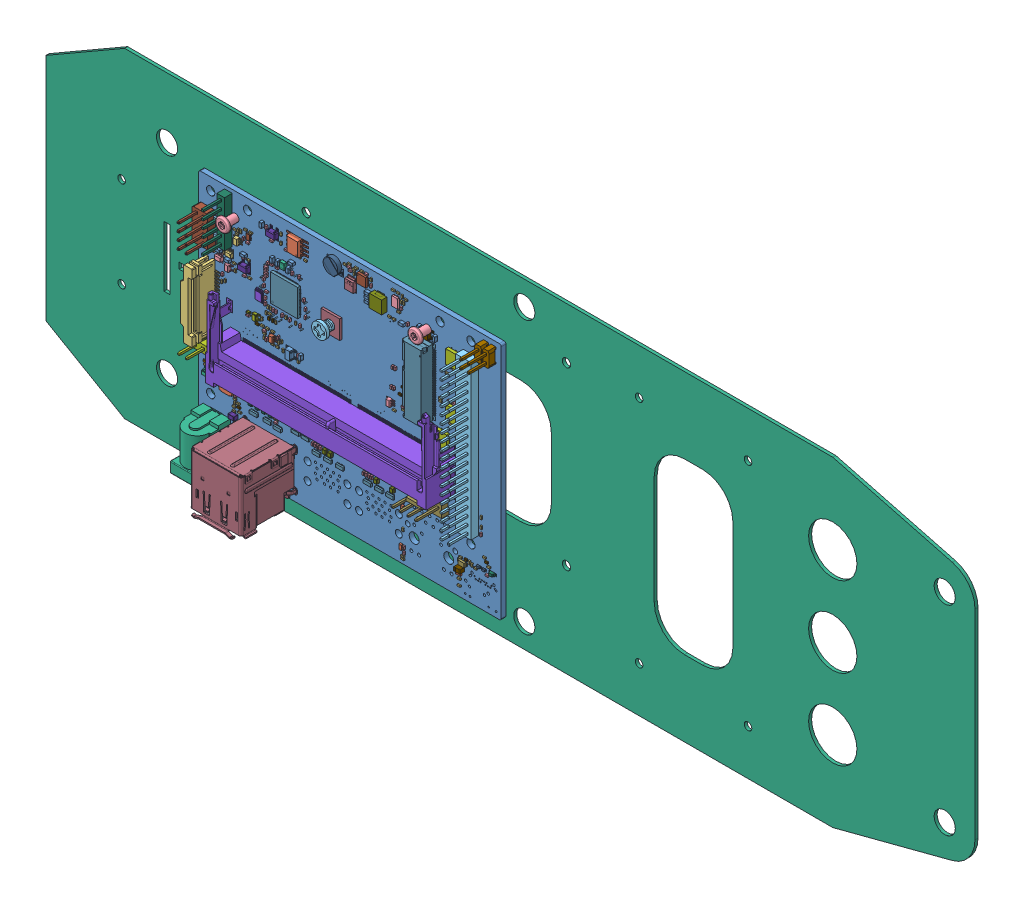
SolidWorks assembly Assemblage, configuration Défaut. Lengths in mm.
Overall size (307 106 29.95).
397 component instances, 67 part files, 3 mates.
Components (placement in the parent):
- P3450_P3449_A02_P3448_A02-1: P3450_P3449_A02_P3448_A02 [Défaut] at (-61.123 -7.2798 -13.0275) size (100 81.03 30.21)
  - 142-13449-1000-A02_ASM-1: 142-13449-1000-A02_ASM [Défaut] at origin size (100 81.03 22.88)
    - 142-13449-1000-A02-1: 142-13449-1000-A02 [Défaut] at origin size (100 79 1.57)
    - 315-1109-000_1-1: 315-1109-000_1 [Défaut] at (5.6 4.9 1.575) x (-1 0 0) z (0 0 1) size (4.5 3.5 0.8)
    - 0402_H040-1: 0402_H040 [Défaut] at (8 -0.825 1.575) size (1 0.5 0.4)
    - 0402_H060-1: 0402_H060 [Défaut] at (1 5 1.575) x (0 -1 0) z (0 0 1) size (1 0.5 0.6)
    - 0402_H040-2: 0402_H040 [Défaut] at (9.9 -0.3 1.575) size (1 0.5 0.4)
    - 0402_H040-3: 0402_H040 [Défaut] at (8.296 51.194 1.575) x (-1 0 0) z (0 0 1) size (1 0.5 0.4)
    - 0402_H040-4: 0402_H040 [Défaut] at (76.2 36.9 1.575) x (-1 0 0) z (0 0 1) size (1 0.5 0.4)
    - 0402_H040-5: 0402_H040 [Défaut] at (37.8 2.87 1.575) x (0 -1 0) z (0 0 1) size (1 0.5 0.4)
    - 0402_H040-6: 0402_H040 [Défaut] at (38.6 2.87 1.575) x (0 -1 0) z (0 0 1) size (1 0.5 0.4)
    - 0402_H060-2: 0402_H060 [Défaut] at (14.2 7.7 1.575) x (0 -1 0) z (0 0 1) size (1 0.5 0.6)
    - 0402_H040-7: 0402_H040 [Défaut] at (64 27.5 1.575) x (-1 0 0) z (0 0 1) size (1 0.5 0.4)
    - 0402_H060-3: 0402_H060 [Défaut] at (18.6 43.15 1.575) x (-1 0 0) z (0 0 1) size (1 0.5 0.6)
    - 0402_H060-4: 0402_H060 [Défaut] at (65.5 52.8 1.575) x (0 1 0) z (0 0 1) size (1 0.5 0.6)
    - 0402_H060-5: 0402_H060 [Défaut] at (64 28.4 1.575) x (-1 0 0) z (0 0 1) size (1 0.5 0.6)
    - 0402_H040-8: 0402_H040 [Défaut] at (60.95 25.85 1.575) size (1 0.5 0.4)
    - 0402_H060-6: 0402_H060 [Défaut] at (17.3 7.7 1.575) x (0 -1 0) z (0 0 1) size (1 0.5 0.6)
    - 0402_H060-7: 0402_H060 [Défaut] at (18.6 7.7 1.575) x (0 -1 0) z (0 0 1) size (1 0.5 0.6)
    - 0402_H060-8: 0402_H060 [Défaut] at (12.9 7.7 1.575) x (0 -1 0) z (0 0 1) size (1 0.5 0.6)
    - 0402_H060-9: 0402_H060 [Défaut] at (80.9 37.7 1.575) x (-1 0 0) z (0 0 1) size (1 0.5 0.6)
    - 0402_H040-9: 0402_H040 [Défaut] at (79.5 31.3 1.575) size (1 0.5 0.4)
    - 0402_H040-10: 0402_H040 [Défaut] at (81 31.3 1.575) x (-1 0 0) z (0 0 1) size (1 0.5 0.4)
    - 0402_H060-10: 0402_H060 [Défaut] at (79.3 37.7 1.575) size (1 0.5 0.6)
    - 0402_H060-11: 0402_H060 [Défaut] at (74.8 4.05 1.575) x (-1 0 0) z (0 0 1) size (1 0.5 0.6)
    - 0402_H040-11: 0402_H040 [Défaut] at (65.675 6.15 1.575) x (0 -1 0) z (0 0 1) size (1 0.5 0.4)
    - 0402_H060-12: 0402_H060 [Défaut] at (67.7 6.85 1.575) x (0 1 0) z (0 0 1) size (1 0.5 0.6)
    - 0402_H040-12: 0402_H040 [Défaut] at (64.475 5.8 1.575) x (-1 0 0) z (0 0 1) size (1 0.5 0.4)
    - 0402_H040-13: 0402_H040 [Défaut] at (67.725 5.325 1.575) x (0 1 0) z (0 0 1) size (1 0.5 0.4)
    - 0402_H060-13: 0402_H060 [Défaut] at (46.1 59.45 1.575) size (1 0.5 0.6)
    - 0402_H040-14: 0402_H040 [Défaut] at (44.65 59.45 1.575) size (1 0.5 0.4)
    - 0402_H040-15: 0402_H040 [Défaut] at (46.1 60.25 1.575) size (1 0.5 0.4)
    - 0402_H060-14: 0402_H060 [Défaut] at (53.35 57.7 1.575) x (0 -1 0) z (0 0 1) size (1 0.5 0.6)
    - 0402_H040-16: 0402_H040 [Défaut] at (47.6 59.45 1.575) size (1 0.5 0.4)
    - 0402_H040-17: 0402_H040 [Défaut] at (48.4 60.25 1.575) size (1 0.5 0.4)
    - 0402_H040-18: 0402_H040 [Défaut] at (47.7 58.325 1.575) x (0 1 0) z (0 0 1) size (1 0.5 0.4)
    - 0402_H060-15: 0402_H060 [Défaut] at (46.5 58.65 1.575) x (-1 0 0) z (0 0 1) size (1 0.5 0.6)
    - 0402_H060-16: 0402_H060 [Défaut] at (51.8 60.25 1.575) size (1 0.5 0.6)
    - 0402_H040-19: 0402_H040 [Défaut] at (53.35 59.4 1.575) x (0 -1 0) z (0 0 1) size (1 0.5 0.4)
    - 0402_H040-20: 0402_H040 [Défaut] at (50.2 60.25 1.575) x (-1 0 0) z (0 0 1) size (1 0.5 0.4)
    - 0402_H060-17: 0402_H060 [Défaut] at (18.6 43.95 1.575) x (-1 0 0) z (0 0 1) size (1 0.5 0.6)
    - 0402_H060-18: 0402_H060 [Défaut] at (52.75 2.9 1.575) x (0 -1 0) z (0 0 1) size (1 0.5 0.6)
    - 0402_H060-19: 0402_H060 [Défaut] at (22.35 47.4 1.575) x (-1 0 0) z (0 0 1) size (1 0.5 0.6)
    - 0402_H060-20: 0402_H060 [Défaut] at (20.55 47.4 1.575) x (-1 0 0) z (0 0 1) size (1 0.5 0.6)
    - 0402_H060-21: 0402_H060 [Défaut] at (21.95 34.55 1.575) x (0 -1 0) z (0 0 1) size (1 0.5 0.6)
    - 0402_H060-22: 0402_H060 [Défaut] at (21.05 34.55 1.575) x (0 -1 0) z (0 0 1) size (1 0.5 0.6)
    - 0402_H060-23: 0402_H060 [Défaut] at (53.55 2.9 1.575) x (0 -1 0) z (0 0 1) size (1 0.5 0.6)
    - 0402_H060-24: 0402_H060 [Défaut] at (25.4 54 1.575) x (-1 0 0) z (0 0 1) size (1 0.5 0.6)
    - 0402_H060-25: 0402_H060 [Défaut] at (24 34.58 1.575) x (0 -1 0) z (0 0 1) size (1 0.5 0.6)
    - 0402_H040-21: 0402_H040 [Défaut] at (55.6 2.95 1.575) x (0 -1 0) z (0 0 1) size (1 0.5 0.4)
    - 0402_H040-22: 0402_H040 [Défaut] at (20.13 34.53 1.575) x (0 1 0) z (0 0 1) size (1 0.5 0.4)
    - 0402_H060-26: 0402_H060 [Défaut] at (18.4 35.15 1.575) x (0 1 0) z (0 0 1) size (1 0.5 0.6)
    - 0402_H060-27: 0402_H060 [Défaut] at (18.4 36.75 1.575) x (0 1 0) z (0 0 1) size (1 0.5 0.6)
    - 0402_H040-23: 0402_H040 [Défaut] at (39.6 2.87 1.575) x (0 -1 0) z (0 0 1) size (1 0.5 0.4)
    - 0402_H040-24: 0402_H040 [Défaut] at (40.4 2.87 1.575) x (0 -1 0) z (0 0 1) size (1 0.5 0.4)
    - 0402_H040-25: 0402_H040 [Défaut] at (60.95 2.95 1.575) x (0 -1 0) z (0 0 1) size (1 0.5 0.4)
    - 0402_H040-26: 0402_H040 [Défaut] at (60.15 2.95 1.575) x (0 -1 0) z (0 0 1) size (1 0.5 0.4)
    - 0402_H040-27: 0402_H040 [Défaut] at (54.8 2.95 1.575) x (0 -1 0) z (0 0 1) size (1 0.5 0.4)
    - 0402_H040-28: 0402_H040 [Défaut] at (31.6 54 1.575) size (1 0.5 0.4)
    - 0402_H040-29: 0402_H040 [Défaut] at (27.4 54 1.575) size (1 0.5 0.4)
    - 0402_H040-30: 0402_H040 [Défaut] at (29.6 54 1.575) x (-1 0 0) z (0 0 1) size (1 0.5 0.4)
    - 0402_H040-31: 0402_H040 [Défaut] at (63.775 -14.475 1.575) size (1 0.5 0.4)
    - 0402_H040-32: 0402_H040 [Défaut] at (63.775 -15.275 1.575) size (1 0.5 0.4)
    - 0402_H040-33: 0402_H040 [Défaut] at (8.025 41.475 1.575) x (-1 0 0) z (0 0 1) size (1 0.5 0.4)
    - 0402_H060-28: 0402_H060 [Défaut] at (63.95 1.25 1.575) x (0 1 0) z (0 0 1) size (1 0.5 0.6)
    - 0402_H060-29: 0402_H060 [Défaut] at (2.95 54.05 1.575) x (0 1 0) z (0 0 1) size (1 0.5 0.6)
    - 0402_H040-34: 0402_H040 [Défaut] at (92.2 -3.45 1.575) x (-1 0 0) z (0 0 1) size (1 0.5 0.4)
    - 0402_H060-30: 0402_H060 [Défaut] at (32.85 7.7 1.575) x (0 -1 0) z (0 0 1) size (1 0.5 0.6)
    - 0402_H060-31: 0402_H060 [Défaut] at (27.25 7.7 1.575) x (0 -1 0) z (0 0 1) size (1 0.5 0.6)
    - 0402_H060-32: 0402_H060 [Défaut] at (31.25 7.7 1.575) x (0 -1 0) z (0 0 1) size (1 0.5 0.6)
    - 0402_H060-33: 0402_H060 [Défaut] at (28.85 7.7 1.575) x (0 -1 0) z (0 0 1) size (1 0.5 0.6)
    - 0402_H060-34: 0402_H060 [Défaut] at (32.05 7.7 1.575) x (0 -1 0) z (0 0 1) size (1 0.5 0.6)
    - 0402_H060-35: 0402_H060 [Défaut] at (28.05 7.7 1.575) x (0 -1 0) z (0 0 1) size (1 0.5 0.6)
    - 0402_H060-36: 0402_H060 [Défaut] at (30.45 7.7 1.575) x (0 -1 0) z (0 0 1) size (1 0.5 0.6)
    - 0402_H060-37: 0402_H060 [Défaut] at (29.65 7.7 1.575) x (0 -1 0) z (0 0 1) size (1 0.5 0.6)
    - 0402_H060-38: 0402_H060 [Défaut] at (24.65 6.41 1.575) x (0 -1 0) z (0 0 1) size (1 0.5 0.6)
    - 0402_H060-39: 0402_H060 [Défaut] at (25.85 6.41 1.575) x (0 -1 0) z (0 0 1) size (1 0.5 0.6)
    - 0402_H060-40: 0402_H060 [Défaut] at (4.2 36.5 1.575) x (0 1 0) z (0 0 1) size (1 0.5 0.6)
    - 0402_H060-41: 0402_H060 [Défaut] at (89.7 4.7 1.575) x (0 -1 0) z (0 0 1) size (1 0.5 0.6)
    - 0402_H060-42: 0402_H060 [Défaut] at (82.5 3.8 1.575) x (0 -1 0) z (0 0 1) size (1 0.5 0.6)
    - 0402_H060-43: 0402_H060 [Défaut] at (12.65 49.7 1.575) size (1 0.5 0.6)
    - 0402_H060-44: 0402_H060 [Défaut] at (11.2 50.15 1.575) x (0 -1 0) z (0 0 1) size (1 0.5 0.6)
    - 0402_H060-45: 0402_H060 [Défaut] at (26.5 34.55 1.575) x (0 -1 0) z (0 0 1) size (1 0.5 0.6)
    - 0402_H060-46: 0402_H060 [Défaut] at (29.9 34.5 1.575) x (0 -1 0) z (0 0 1) size (1 0.5 0.6)
    - 0402_H060-47: 0402_H060 [Défaut] at (31.7 40.15 1.575) x (0 1 0) z (0 0 1) size (1 0.5 0.6)
    - 0402_H060-48: 0402_H060 [Défaut] at (31.15 42.5 1.575) x (0 1 0) z (0 0 1) size (1 0.5 0.6)
    - 0402_H060-49: 0402_H060 [Défaut] at (19.2 47.05 1.575) x (0 1 0) z (0 0 1) size (1 0.5 0.6)
    - 0402_H060-50: 0402_H060 [Défaut] at (17.95 42 1.575) x (0 -1 0) z (0 0 1) size (1 0.5 0.6)
    - 0402_H060-51: 0402_H060 [Défaut] at (27.3 48.25 1.575) x (0 1 0) z (0 0 1) size (1 0.5 0.6)
    - 0402_H060-52: 0402_H060 [Défaut] at (31.7 37.85 1.575) x (0 -1 0) z (0 0 1) size (1 0.5 0.6)
    - 0402_H060-53: 0402_H060 [Défaut] at (29.6 48.35 1.575) x (0 1 0) z (0 0 1) size (1 0.5 0.6)
    - 0402_H060-54: 0402_H060 [Défaut] at (18.8 38.75 1.575) x (-1 0 0) z (0 0 1) size (1 0.5 0.6)
    - 0402_H060-55: 0402_H060 [Défaut] at (18.7 57.2 1.575) x (0 -1 0) z (0 0 1) size (1 0.5 0.6)
    - 0402_H060-56: 0402_H060 [Défaut] at (34.1 2.9 1.575) x (0 -1 0) z (0 0 1) size (1 0.5 0.6)
    - 0402_H060-57: 0402_H060 [Défaut] at (35.8 2.9 1.575) x (0 -1 0) z (0 0 1) size (1 0.5 0.6)
    - 0402_H060-58: 0402_H060 [Défaut] at (34.9 2.9 1.575) x (0 -1 0) z (0 0 1) size (1 0.5 0.6)
    - 0402_H060-59: 0402_H060 [Défaut] at (36.6 2.9 1.575) x (0 -1 0) z (0 0 1) size (1 0.5 0.6)
    - 0402_H060-60: 0402_H060 [Défaut] at (11.325 44.725 1.575) size (1 0.5 0.6)
    - 0402_H060-61: 0402_H060 [Défaut] at (50.95 2.9 1.575) x (0 -1 0) z (0 0 1) size (1 0.5 0.6)
    - 0402_H060-62: 0402_H060 [Défaut] at (51.75 2.9 1.575) x (0 -1 0) z (0 0 1) size (1 0.5 0.6)
    - 0402_H060-63: 0402_H060 [Défaut] at (11.55 39.7 1.575) size (1 0.5 0.6)
    - 0402_H060-64: 0402_H060 [Défaut] at (9.5 -8.5 1.575) x (-1 0 0) z (0 0 1) size (1 0.5 0.6)
    - 0402_H060-65: 0402_H060 [Défaut] at (61.35 38.05 1.575) x (0 -1 0) z (0 0 1) size (1 0.5 0.6)
    - 0402_H060-66: 0402_H060 [Défaut] at (60.55 38.05 1.575) x (0 -1 0) z (0 0 1) size (1 0.5 0.6)
    - 0402_H060-67: 0402_H060 [Défaut] at (29.3 25.65 1.575) x (0 -1 0) z (0 0 1) size (1 0.5 0.6)
    - 0402_H060-68: 0402_H060 [Défaut] at (63.3 56.2 1.575) x (0 1 0) z (0 0 1) size (1 0.5 0.6)
    - 0402_H060-69: 0402_H060 [Défaut] at (20.5 54.2 1.575) size (1 0.5 0.6)
    - 0402_H060-70: 0402_H060 [Défaut] at (60.1 32.15 1.575) x (0 1 0) z (0 0 1) size (1 0.5 0.6)
    - 0402_H060-71: 0402_H060 [Défaut] at (60.9 32.15 1.575) x (0 1 0) z (0 0 1) size (1 0.5 0.6)
    - 0402_H060-72: 0402_H060 [Défaut] at (18.6 44.85 1.575) size (1 0.5 0.6)
    - 0402_H060-73: 0402_H060 [Défaut] at (18.6 45.65 1.575) size (1 0.5 0.6)
    - 0402_H060-74: 0402_H060 [Défaut] at (18.1 27.25 1.575) size (1 0.5 0.6)
    - 0402_H060-75: 0402_H060 [Défaut] at (15.1 7.7 1.575) x (0 -1 0) z (0 0 1) size (1 0.5 0.6)
    - 0402_H060-76: 0402_H060 [Défaut] at (16.4 7.7 1.575) x (0 -1 0) z (0 0 1) size (1 0.5 0.6)
    - 0402_H060-77: 0402_H060 [Défaut] at (20.8 7.7 1.575) x (0 -1 0) z (0 0 1) size (1 0.5 0.6)
    - 0402_H060-78: 0402_H060 [Défaut] at (19.5 7.7 1.575) x (0 -1 0) z (0 0 1) size (1 0.5 0.6)
    - 0402_H060-79: 0402_H060 [Défaut] at (21.9 2.8 1.575) size (1 0.5 0.6)
    - 0402_H060-80: 0402_H060 [Défaut] at (12.75 29 1.575) size (1 0.5 0.6)
    - 0402_H060-81: 0402_H060 [Défaut] at (10.225 5.1 1.575) size (1 0.5 0.6)
    - 0402_H060-82: 0402_H060 [Défaut] at (22.8 27.65 1.575) x (0 1 0) z (0 0 1) size (1 0.5 0.6)
    - 0402_H060-83: 0402_H060 [Défaut] at (18.85 25.15 1.575) x (0 -1 0) z (0 0 1) size (1 0.5 0.6)
    - 0402_H060-84: 0402_H060 [Défaut] at (17.95 40.1 1.575) x (0 1 0) z (0 0 1) size (1 0.5 0.6)
    - 0402_H040-35: 0402_H040 [Défaut] at (20.8 6.2 1.575) x (0 1 0) z (0 0 1) size (1 0.5 0.4)
    - 0402_H040-36: 0402_H040 [Défaut] at (76 22.7 1.575) size (1 0.5 0.4)
    - 0402_H040-37: 0402_H040 [Défaut] at (23.7 26.85 1.575) x (0 1 0) z (0 0 1) size (1 0.5 0.4)
    - 0402_H040-38: 0402_H040 [Défaut] at (18 25.15 1.575) x (0 1 0) z (0 0 1) size (1 0.5 0.4)
    - 0402_H040-39: 0402_H040 [Défaut] at (17.3 28.25 1.575) x (-1 0 0) z (0 0 1) size (1 0.5 0.4)
    - 0402_H040-40: 0402_H040 [Défaut] at (13.15 4.2 1.575) x (0 -1 0) z (0 0 1) size (1 0.5 0.4)
    - 0402_H040-41: 0402_H040 [Défaut] at (17.2 30.15 1.575) x (0 -1 0) z (0 0 1) size (1 0.5 0.4)
    - 0402_H040-42: 0402_H040 [Défaut] at (14.2 6.2 1.575) x (0 1 0) z (0 0 1) size (1 0.5 0.4)
    - 0402_H040-43: 0402_H040 [Défaut] at (12.9 6.2 1.575) x (0 1 0) z (0 0 1) size (1 0.5 0.4)
    - 0402_H040-44: 0402_H040 [Défaut] at (15.1 6.2 1.575) x (0 1 0) z (0 0 1) size (1 0.5 0.4)
    - 0402_H040-45: 0402_H040 [Défaut] at (16.4 6.2 1.575) x (0 1 0) z (0 0 1) size (1 0.5 0.4)
    - 0402_H040-46: 0402_H040 [Défaut] at (19.5 6.2 1.575) x (0 1 0) z (0 0 1) size (1 0.5 0.4)
    - 0402_H040-47: 0402_H040 [Défaut] at (17.3 6.2 1.575) x (0 1 0) z (0 0 1) size (1 0.5 0.4)
    - 0402_H040-48: 0402_H040 [Défaut] at (18.6 6.2 1.575) x (0 1 0) z (0 0 1) size (1 0.5 0.4)
    - 0402_H040-49: 0402_H040 [Défaut] at (24.2 24.55 1.575) x (0 1 0) z (0 0 1) size (1 0.5 0.4)
    - 0402_H040-50: 0402_H040 [Défaut] at (23.5 54.9 1.575) x (0 1 0) z (0 0 1) size (1 0.5 0.4)
    - 0402_H040-51: 0402_H040 [Défaut] at (13.2 39.75 1.575) x (-1 0 0) z (0 0 1) size (1 0.5 0.4)
    - 0402_H040-52: 0402_H040 [Défaut] at (80.7 47.4 1.575) x (-1 0 0) z (0 0 1) size (1 0.5 0.4)
    - 0402_H040-53: 0402_H040 [Défaut] at (77.5 22.7 1.575) x (-1 0 0) z (0 0 1) size (1 0.5 0.4)
    - 0402_H040-54: 0402_H040 [Défaut] at (9.25 -12.75 1.575) x (-1 0 0) z (0 0 1) size (1 0.5 0.4)
    - 0402_H040-55: 0402_H040 [Défaut] at (9.25 -11.95 1.575) x (-1 0 0) z (0 0 1) size (1 0.5 0.4)
    - 0402_H040-56: 0402_H040 [Défaut] at (64.475 6.7 1.575) size (1 0.5 0.4)
    - 0402_H040-57: 0402_H040 [Défaut] at (29.3 24 1.575) x (0 1 0) z (0 0 1) size (1 0.5 0.4)
    - 0402_H040-58: 0402_H040 [Défaut] at (64.2 32.5 1.575) x (0 1 0) z (0 0 1) size (1 0.5 0.4)
    - 0402_H040-59: 0402_H040 [Défaut] at (64.15 47.45 1.575) x (0 -1 0) z (0 0 1) size (1 0.5 0.4)
    - 0402_H040-60: 0402_H040 [Défaut] at (64.2 31 1.575) x (0 -1 0) z (0 0 1) size (1 0.5 0.4)
    - 0402_H040-61: 0402_H040 [Défaut] at (76.2 36.1 1.575) x (-1 0 0) z (0 0 1) size (1 0.5 0.4)
    - 0402_H040-62: 0402_H040 [Défaut] at (78.4 45.15 1.575) size (1 0.5 0.4)
    - 0402_H040-63: 0402_H040 [Défaut] at (81.7 38.6 1.575) size (1 0.5 0.4)
    - 0402_H040-64: 0402_H040 [Défaut] at (81.7 39.4 1.575) size (1 0.5 0.4)
    - 0402_H040-65: 0402_H040 [Défaut] at (59.35 51.825 1.575) size (1 0.5 0.4)
    - 0402_H040-66: 0402_H040 [Défaut] at (60.825 51.825 1.575) x (-1 0 0) z (0 0 1) size (1 0.5 0.4)
    - 0402_H040-67: 0402_H040 [Défaut] at (89.7 9.5 1.575) x (0 1 0) z (0 0 1) size (1 0.5 0.4)
    - 0402_H040-68: 0402_H040 [Défaut] at (89.7 6.7 1.575) x (0 1 0) z (0 0 1) size (1 0.5 0.4)
    - 0402_H040-69: 0402_H040 [Défaut] at (3.9 34.2 1.575) x (0 -1 0) z (0 0 1) size (1 0.5 0.4)
    - 0402_H040-70: 0402_H040 [Défaut] at (5.1 35 1.575) x (0 1 0) z (0 0 1) size (1 0.5 0.4)
    - 0402_H040-71: 0402_H040 [Défaut] at (32.85 5.81 1.575) x (0 -1 0) z (0 0 1) size (1 0.5 0.4)
    - 0402_H040-72: 0402_H040 [Défaut] at (32.05 5.81 1.575) x (0 -1 0) z (0 0 1) size (1 0.5 0.4)
    - 0402_H040-73: 0402_H040 [Défaut] at (27.25 5.81 1.575) x (0 -1 0) z (0 0 1) size (1 0.5 0.4)
    - 0402_H040-74: 0402_H040 [Défaut] at (28.05 5.81 1.575) x (0 -1 0) z (0 0 1) size (1 0.5 0.4)
    - 0402_H040-75: 0402_H040 [Défaut] at (31.25 5.81 1.575) x (0 -1 0) z (0 0 1) size (1 0.5 0.4)
    - 0402_H040-76: 0402_H040 [Défaut] at (30.45 5.81 1.575) x (0 -1 0) z (0 0 1) size (1 0.5 0.4)
    - 0402_H040-77: 0402_H040 [Défaut] at (28.85 5.81 1.575) x (0 -1 0) z (0 0 1) size (1 0.5 0.4)
    - 0402_H040-78: 0402_H040 [Défaut] at (29.65 5.81 1.575) x (0 -1 0) z (0 0 1) size (1 0.5 0.4)
    - 0402_H040-79: 0402_H040 [Défaut] at (13.5 52.9 1.575) x (-1 0 0) z (0 0 1) size (1 0.5 0.4)
    - 0402_H040-80: 0402_H040 [Défaut] at (22.35 4 1.575) x (0 -1 0) z (0 0 1) size (1 0.5 0.4)
    - 0402_H040-81: 0402_H040 [Défaut] at (21.55 4 1.575) x (0 1 0) z (0 0 1) size (1 0.5 0.4)
    - 0402_H040-82: 0402_H040 [Défaut] at (25.85 4.9 1.575) x (0 -1 0) z (0 0 1) size (1 0.5 0.4)
    - 0402_H040-83: 0402_H040 [Défaut] at (11.8 52.9 1.575) size (1 0.5 0.4)
    - 0402_H040-84: 0402_H040 [Défaut] at (9.432 51.594 1.575) x (0 -1 0) z (0 0 1) size (1 0.5 0.4)
    - 0402_H040-85: 0402_H040 [Défaut] at (8.975 50.3 1.575) size (1 0.5 0.4)
    - 0402_H040-86: 0402_H040 [Défaut] at (82.8 -5.3 1.575) x (-1 0 0) z (0 0 1) size (1 0.5 0.4)
    - 0402_H040-87: 0402_H040 [Défaut] at (82.4 -11.6 1.575) x (-1 0 0) z (0 0 1) size (1 0.5 0.4)
    - 0402_H040-88: 0402_H040 [Défaut] at (22.8 26.05 1.575) x (0 1 0) z (0 0 1) size (1 0.5 0.4)
    - 0402_H040-89: 0402_H040 [Défaut] at (20.8 28.25 1.575) size (1 0.5 0.4)
    - 0402_H040-90: 0402_H040 [Défaut] at (20.8 24.65 1.575) x (-1 0 0) z (0 0 1) size (1 0.5 0.4)
    - 0402_H040-91: 0402_H040 [Défaut] at (18.1 26.45 1.575) size (1 0.5 0.4)
    - 0402_H040-92: 0402_H040 [Défaut] at (24.65 8.41 1.575) x (0 1 0) z (0 0 1) size (1 0.5 0.4)
    - 0402_H040-93: 0402_H040 [Défaut] at (25.85 8.41 1.575) x (0 1 0) z (0 0 1) size (1 0.5 0.4)
    - 0402_H040-94: 0402_H040 [Défaut] at (3.8 54.4 1.575) x (0 -1 0) z (0 0 1) size (1 0.5 0.4)
    - 0402_H040-95: 0402_H040 [Défaut] at (2.45 44.45 1.575) x (0 -1 0) z (0 0 1) size (1 0.5 0.4)
    - 0402_H040-96: 0402_H040 [Défaut] at (24.65 4.9 1.575) x (0 1 0) z (0 0 1) size (1 0.5 0.4)
    - 0402_H040-97: 0402_H040 [Défaut] at (22.15 7.6 1.575) x (-1 0 0) z (0 0 1) size (1 0.5 0.4)
    - 0402_H040-98: 0402_H040 [Défaut] at (79.2 47.4 1.575) size (1 0.5 0.4)
    - 0402_H040-99: 0402_H040 [Défaut] at (19 28.25 1.575) size (1 0.5 0.4)
    - 0402_H040-100: 0402_H040 [Défaut] at (9.65 9.7 1.575) x (0 -1 0) z (0 0 1) size (1 0.5 0.4)
    - 0402_H040-101: 0402_H040 [Défaut] at (28.35 34.45 1.575) x (0 1 0) z (0 0 1) size (1 0.5 0.4)
    - 0402_H040-102: 0402_H040 [Défaut] at (25.2 34.55 1.575) x (0 1 0) z (0 0 1) size (1 0.5 0.4)
    - 0402_H040-103: 0402_H040 [Défaut] at (10.625 6.35 1.575) x (0 -1 0) z (0 0 1) size (1 0.5 0.4)
    - 0402_H040-104: 0402_H040 [Défaut] at (9.825 6.35 1.575) x (0 1 0) z (0 0 1) size (1 0.5 0.4)
    - 0402_H040-105: 0402_H040 [Défaut] at (4.775 42.975 1.575) x (0 1 0) z (0 0 1) size (1 0.5 0.4)
    - 0402_H040-106: 0402_H040 [Défaut] at (19.8 32.9 1.575) x (-1 0 0) z (0 0 1) size (1 0.5 0.4)
    - 0402_H040-107: 0402_H040 [Défaut] at (22.35 24.65 1.575) x (-1 0 0) z (0 0 1) size (1 0.5 0.4)
    - 0402_H040-108: 0402_H040 [Défaut] at (62.4 54.7 1.575) size (1 0.5 0.4)
    - 0402_H040-109: 0402_H040 [Défaut] at (62.2 60.05 1.575) x (-1 0 0) z (0 0 1) size (1 0.5 0.4)
    - 0402_H040-110: 0402_H040 [Défaut] at (23.5 57.5 1.575) x (0 1 0) z (0 0 1) size (1 0.5 0.4)
    - 0402_H040-111: 0402_H040 [Défaut] at (12.8 44.725 1.575) size (1 0.5 0.4)
    - 0402_H040-112: 0402_H040 [Défaut] at (21.8 31.45 1.575) x (0 1 0) z (0 0 1) size (1 0.5 0.4)
    - 0402_H040-113: 0402_H040 [Défaut] at (19.25 34.55 1.575) x (0 1 0) z (0 0 1) size (1 0.5 0.4)
    - 0402_H040-114: 0402_H040 [Défaut] at (0.95 41.55 1.575) size (1 0.5 0.4)
    - 0402_H040-115: 0402_H040 [Défaut] at (64.1 58 1.575) x (0 1 0) z (0 0 1) size (1 0.5 0.4)
    - 0402_H040-116: 0402_H040 [Défaut] at (63.3 58 1.575) x (0 -1 0) z (0 0 1) size (1 0.5 0.4)
    - 0402_H040-117: 0402_H040 [Défaut] at (63.55 59.7 1.575) x (0 -1 0) z (0 0 1) size (1 0.5 0.4)
    - 0402_H060-85: 0402_H060 [Défaut] at (71.175 4 1.575) x (-1 0 0) z (0 0 1) size (1 0.5 0.6)
    - 0402_H040-118: 0402_H040 [Défaut] at (86.6 -5.6 1.575) x (0 1 0) z (0 0 1) size (1 0.5 0.4)
    - 0402_H040-119: 0402_H040 [Défaut] at (85.8 -5.3 1.575) x (0 1 0) z (0 0 1) size (1 0.5 0.4)
    - 0402_H040-120: 0402_H040 [Défaut] at (10.25 51.6 1.575) x (0 1 0) z (0 0 1) size (1 0.5 0.4)
    - 0402_H040-121: 0402_H040 [Défaut] at (80.5 28.55 1.575) size (1 0.5 0.4)
    - 0402_H040-122: 0402_H040 [Défaut] at (13.95 4.2 1.575) x (0 -1 0) z (0 0 1) size (1 0.5 0.4)
    - 0402_H040-123: 0402_H040 [Défaut] at (15.35 4.2 1.575) x (0 -1 0) z (0 0 1) size (1 0.5 0.4)
    - 0402_H040-124: 0402_H040 [Défaut] at (16.15 4.2 1.575) x (0 -1 0) z (0 0 1) size (1 0.5 0.4)
    - 0402_H040-125: 0402_H040 [Défaut] at (20.55 4.2 1.575) x (0 -1 0) z (0 0 1) size (1 0.5 0.4)
    - 0402_H040-126: 0402_H040 [Défaut] at (19.75 4.2 1.575) x (0 -1 0) z (0 0 1) size (1 0.5 0.4)
    - 0402_H040-127: 0402_H040 [Défaut] at (17.6 4.2 1.575) x (0 -1 0) z (0 0 1) size (1 0.5 0.4)
    - 0402_H040-128: 0402_H040 [Défaut] at (18.4 4.2 1.575) x (0 -1 0) z (0 0 1) size (1 0.5 0.4)
    - 0402_H060-86: 0402_H060 [Défaut] at (64.25 -13.325 1.575) x (0 -1 0) z (0 0 1) size (1 0.5 0.6)
    - 0402_H060-87: 0402_H060 [Défaut] at (64.225 -11.825 1.575) x (0 1 0) z (0 0 1) size (1 0.5 0.6)
    - 0402_H040-129: 0402_H040 [Défaut] at (63.8 -6.85 1.575) x (0 1 0) z (0 0 1) size (1 0.5 0.4)
    - 0402_H040-130: 0402_H040 [Défaut] at (81.7 41.95 1.575) size (1 0.5 0.4)
    - 0402_H040-131: 0402_H040 [Défaut] at (87.75 -6 1.575) x (-1 0 0) z (0 0 1) size (1 0.5 0.4)
    - 0402_H040-132: 0402_H040 [Défaut] at (82.4 -13.6 1.575) x (-1 0 0) z (0 0 1) size (1 0.5 0.4)
    - 0402_H060-88: 0402_H060 [Défaut] at (91.75 -5.95 1.575) size (1 0.5 0.6)
    - 0402_H040-133: 0402_H040 [Défaut] at (3.65 49.25 1.575) x (0 -1 0) z (0 0 1) size (1 0.5 0.4)
    - 0402_H040-134: 0402_H040 [Défaut] at (2.45 49.25 1.575) x (0 1 0) z (0 0 1) size (1 0.5 0.4)
    - 0402_H040-135: 0402_H040 [Défaut] at (90.75 -1.45 1.575) x (-1 0 0) z (0 0 1) size (1 0.5 0.4)
    - 0402_H040-136: 0402_H040 [Défaut] at (8.45 39.55 1.575) x (0 -1 0) z (0 0 1) size (1 0.5 0.4)
    - 0402_H060-89: 0402_H060 [Défaut] at (8.85 -5.25 1.575) x (-1 0 0) z (0 0 1) size (1 0.5 0.6)
    - 0402_H040-137: 0402_H040 [Défaut] at (18.6 32.55 1.575) x (0 1 0) z (0 0 1) size (1 0.5 0.4)
    - 0402_H060-90: 0402_H060 [Défaut] at (4.5 44.45 1.575) x (0 1 0) z (0 0 1) size (1 0.5 0.6)
    - 0402_H040-138: 0402_H040 [Défaut] at (8.35 2.75 1.575) size (1 0.5 0.4)
    - 0402_H040-139: 0402_H040 [Défaut] at (9.4 1.95 1.575) size (1 0.5 0.4)
    - 0402_H040-140: 0402_H040 [Défaut] at (8.2 1.55 1.575) x (0 1 0) z (0 0 1) size (1 0.5 0.4)
    - 0402_H060-91: 0402_H060 [Défaut] at (8.5 3.875 1.575) x (0 -1 0) z (0 0 1) size (1 0.5 0.6)
    - 0402_H060-92: 0402_H060 [Défaut] at (-0.8 41.5 1.575) x (-1 0 0) z (0 0 1) size (1 0.5 0.6)
    - 0402_H040-141: 0402_H040 [Défaut] at (-1.35 7.75 1.575) size (1 0.5 0.4)
    - 0402_H040-142: 0402_H040 [Défaut] at (8 0.425 1.575) size (1 0.5 0.4)
    - 0402_H040-143: 0402_H040 [Défaut] at (67.9 4.025 1.575) x (-1 0 0) z (0 0 1) size (1 0.5 0.4)
    - 0402_H040-144: 0402_H040 [Défaut] at (60.6 60.05 1.575) x (-1 0 0) z (0 0 1) size (1 0.5 0.4)
    - 0402_H040-145: 0402_H040 [Défaut] at (72.85 4 1.575) x (-1 0 0) z (0 0 1) size (1 0.5 0.4)
    - 0402_H040-146: 0402_H040 [Défaut] at (64.8 59.35 1.575) size (1 0.5 0.4)
    - 0402_H040-147: 0402_H040 [Défaut] at (7.2 7.3 1.575) size (1 0.5 0.4)
    - 0402_H040-148: 0402_H040 [Défaut] at (8.5 5.35 1.575) x (0 1 0) z (0 0 1) size (1 0.5 0.4)
    - 0402_H040-149: 0402_H040 [Défaut] at (8.475 7.075 1.575) x (0 1 0) z (0 0 1) size (1 0.5 0.4)
    - VIRTUAL_SHORT-1: VIRTUAL_SHORT [Défaut] at (23.5 32.9 1.575) x (0 1 0) z (0 0 1) size (0.25 0.25 1)
    - VIRTUAL_SHORT-2: VIRTUAL_SHORT [Défaut] at (26.85 32.85 1.575) x (0 1 0) z (0 0 1) size (0.25 0.25 1)
    - VIRTUAL_SHORT-3: VIRTUAL_SHORT [Défaut] at (30.6 33.8 1.575) x (0 1 0) z (0 0 1) size (0.25 0.25 1)
    - VIRTUAL_SHORT-4: VIRTUAL_SHORT [Défaut] at (32.65 39.75 1.575) x (-1 0 0) z (0 0 1) size (0.25 0.25 1)
    - VIRTUAL_SHORT-5: VIRTUAL_SHORT [Défaut] at (31.85 42.1 1.575) x (-1 0 0) z (0 0 1) size (0.25 0.25 1)
    - VIRTUAL_SHORT-6: VIRTUAL_SHORT [Défaut] at (17.35 42.4 1.575) size (0.25 0.25 1)
    - VIRTUAL_SHORT-7: VIRTUAL_SHORT [Défaut] at (18.6 46.6 1.575) size (0.25 0.25 1)
    - VIRTUAL_SHORT-8: VIRTUAL_SHORT [Défaut] at (20.9 32.9 1.575) x (0 1 0) z (0 0 1) size (0.25 0.25 1)
    - VIRTUAL_SHORT-9: VIRTUAL_SHORT [Défaut] at (28.6 48.25 1.575) x (0 -1 0) z (0 0 1) size (0.25 0.25 1)
    - VIRTUAL_SHORT-10: VIRTUAL_SHORT [Défaut] at (27.1 49.35 1.575) x (0 -1 0) z (0 0 1) size (0.25 0.25 1)
    - VIRTUAL_SHORT-11: VIRTUAL_SHORT [Défaut] at (22.1 32.95 1.575) x (-1 0 0) z (0 0 1) size (0.25 0.25 1)
    - VIRTUAL_SHORT-12: VIRTUAL_SHORT [Défaut] at (32.65 38.25 1.575) x (-1 0 0) z (0 0 1) size (0.25 0.25 1)
    - VIRTUAL_SHORT-13: VIRTUAL_SHORT [Défaut] at (30.3 48 1.575) x (-1 0 0) z (0 0 1) size (0.25 0.25 1)
    - VIRTUAL_SHORT-14: VIRTUAL_SHORT [Défaut] at (17.15 38.95 1.575) size (0.25 0.25 1)
    - VIRTUAL_SHORT-15: VIRTUAL_SHORT [Défaut] at (17.15 39.7 1.575) size (0.25 0.25 1)
    - VIRTUAL_SHORT-16: VIRTUAL_SHORT [Défaut] at (76.175 4.1 1.575) x (-1 0 0) z (0 0 1) size (0.25 0.25 1)
    - 064-0377-000_2-1: 064-0377-000_2 [Défaut] at (2 -4.75 1.575) x (0 -1 0) z (0 0 1) size (14.63 10.08 14.5)
    - 074-0117-000_2-1: 074-0117-000_2 [Défaut] at (0.254 14.3 1.575) size (5.08 2.54 11.66)
    - 090-0096-000_1-1: 090-0096-000_1 [Défaut] at (3.45 44.4 1.575) x (0 -1 0) z (0 0 1) size (1.2 0.6 0.4)
    - 090-0309-000_1-1: 090-0309-000_1 [Défaut] at (-1.65 8.7 1.575) x (-1 0 0) z (0 0 1) size (1.2 0.6 0.4)
    - 115-1232-000_2-1: 115-1232-000_2 [Défaut] at (1.25 6.5 1.575) x (-1 0 0) z (0 0 1) size (0.9 0.9 0.33)
    - 074-0102-000_4-1: 074-0102-000_4 [Défaut] at (0.254 44.36 1.575) x (0 1 0) z (0 0 1) size (10.16 5.08 11.6)
    - 064-0400-000_1-1: 064-0400-000_1 [Défaut] at (73.75 7.77 1.575) size (10.16 5.8 13.5)
    - MEC_STANDOFF_PTH_620C380P-1: MEC_STANDOFF_PTH_620C380P [Défaut] at (40.276 40.3 1.575) x (0 1 0) z (0 0 1) size (6.2 6.2 0.73)
    - 090-0231-000_1-1: 090-0231-000_1 [Défaut] at (35.3 0.7 1.575) x (-1 0 0) z (0 0 1) size (2.5 1.55 0.55)
    - 090-0231-000_1-2: 090-0231-000_1 [Défaut] at (52.25 0.7 1.575) x (-1 0 0) z (0 0 1) size (2.5 1.55 0.55)
    - 090-0231-000_1-3: 090-0231-000_1 [Défaut] at (56.05 0.7 1.575) size (2.5 1.55 0.55)
    - 090-0231-000_1-4: 090-0231-000_1 [Défaut] at (59.65 0.7 1.575) size (2.5 1.55 0.55)
    - 090-0231-000_1-5: 090-0231-000_1 [Défaut] at (39.1 0.7 1.575) size (2.5 1.55 0.55)
    - 090-0231-000_1-6: 090-0231-000_1 [Défaut] at (43.1 0.7 1.575) size (2.5 1.55 0.55)
    - 090-0231-000_1-7: 090-0231-000_1 [Défaut] at (14.6 1.8 1.575) size (2.5 1.55 0.55)
    - 090-0231-000_1-8: 090-0231-000_1 [Défaut] at (19.1 1.8 1.575) size (2.5 1.55 0.55)
    - 090-0231-000_1-9: 090-0231-000_1 [Défaut] at (22.5 1.4 1.575) size (2.5 1.55 0.55)
    - 090-0231-000_1-10: 090-0231-000_1 [Défaut] at (28.45 3.35 1.575) size (2.5 1.55 0.55)
    - 090-0231-000_1-11: 090-0231-000_1 [Défaut] at (31.65 3.35 1.575) size (2.5 1.55 0.55)
    - 074-0223-000_2-1: 074-0223-000_2 [Défaut] at (5.85 53.25 1.575) x (0 1 0) z (0 0 1) size (15.24 2.54 11.6)
    - 131-0832-000_2-1: 131-0832-000_2 [Défaut] at (56.3 54.7 1.575) x (0 -1 0) z (0 0 1) size (4.96 4.06 1.8)
    - 115-0836-000_1-1: 115-0836-000_1 [Défaut] at (21.1 56.6 1.575) size (2.9 3.58 1.45)
    - 115-0836-000_1-2: 115-0836-000_1 [Défaut] at (11.8 42.3 1.575) size (2.9 3.58 1.45)
    - 315-0620-000_1-1: 315-0620-000_1 [Défaut] at (72.1 53.4 1.575) x (0 -1 0) z (0 0 1) size (2.9 3.58 1.1)
    - 315-1062-000_1-1: 315-1062-000_1 [Défaut] at (26.8 25.15 1.575) x (0 -1 0) z (0 0 1) size (2.9 3.58 1.45)
    - 170-0285-000_1-1: 170-0285-000_1 [Défaut] at (28.72 57.28 1.575) x (0 1 0) z (0 0 1) size (4.9 7.21 1.75)
    - 115-0138-000_1-1: 115-0138-000_1 [Défaut] at (9.15 48.55 1.575) x (0 1 0) z (0 0 1) size (2 2.88 1.1)
    - 115-1821-000_1-1: 115-1821-000_1 [Défaut] at (3.3 40.8 1.575) x (-1 0 0) z (0 0 1) size (2 2.88 1.1)
    - 115-1821-000_1-2: 115-1821-000_1 [Défaut] at (6.25 39.55 1.575) x (0 -1 0) z (0 0 1) size (2 2.88 1.1)
    - 115-0742-000_2-1: 115-0742-000_2 [Défaut] at (3.05 46.85 1.575) size (2 2.88 1.1)
    - 115-0742-000_2-2: 115-0742-000_2 [Défaut] at (3.05 51.65 1.575) x (-1 0 0) z (0 0 1) size (2 2.88 1.1)
    - 115-1821-000_1-3: 115-1821-000_1 [Défaut] at (59.6 27.6 1.575) x (0 1 0) z (0 0 1) size (2 2.88 1.1)
    - 091-0022-000_1-1: 091-0022-000_1 [Défaut] at (-0.95 5.7 1.575) size (2 2.51 1.1)
    - 091-0023-000_1-1: 091-0023-000_1 [Défaut] at (15.25 29.9 1.575) x (0 -1 0) z (0 0 1) size (2 2.51 1.1)
    - 080-1656-000_3-1: 080-1656-000_3 [Défaut] at (44 16.6 1.575) x (-1 0 0) z (0 0 1) size (77.5 25.85 9.66)
    - 090-0243-000_1-1: 090-0243-000_1 [Défaut] at (8.5 -4.1 1.575) x (-1 0 0) z (0 0 1) size (1.41 0.61 0.45)
    - 090-0243-000_1-2: 090-0243-000_1 [Défaut] at (9.95 -3.7 1.575) x (0 1 0) z (0 0 1) size (1.41 0.61 0.45)
    - 090-0243-000_1-3: 090-0243-000_1 [Défaut] at (9.5 -10.95 1.575) x (-1 0 0) z (0 0 1) size (1.41 0.61 0.45)
    - 090-0243-000_1-4: 090-0243-000_1 [Défaut] at (9.8 -6.25 1.575) x (-1 0 0) z (0 0 1) size (1.41 0.61 0.45)
    - 090-0243-000_1-5: 090-0243-000_1 [Défaut] at (9.5 -9.5 1.575) x (-1 0 0) z (0 0 1) size (1.41 0.61 0.45)
    - 090-0172-000_1-1: 090-0172-000_1 [Défaut] at (90.6 -5 1.575) size (1.41 0.61 0.55)
    - 090-0172-000_1-2: 090-0172-000_1 [Défaut] at (88.8 -5 1.575) x (-1 0 0) z (0 0 1) size (1.41 0.61 0.55)
    - 115-2177-000_2-1: 115-2177-000_2 [Défaut] at (12.7 51.35 1.575) x (0 1 0) z (0 0 1) size (1.8 1.71 0.4)
    - 090-0233-000_1-1: 090-0233-000_1 [Défaut] at (83.5 -6.6 1.575) size (3.3 1.3 0.74)
    - 064-0374-000_2-1: 064-0374-000_2 [Défaut] at (19.75 -9.65 1.575) size (18.1 18.55 21.85)
    - 115-2628-000_3-1: 115-2628-000_3 [Défaut] at (25.2 41.2 1.575) size (9.5 9.5 0.9)
    - 092-0073-000_1-1: 092-0073-000_1 [Défaut] at (93.35 -4.75 1.575) x (-1 0 0) z (0 0 1) size (2.46 0.81 0.9)
    - IND_SMD_0402_H060-1: IND_SMD_0402_H060 [Défaut] at (12.85 29.9 1.575) x (-1 0 0) z (0 0 1) size (1 0.5 0.6)
    - 1206_H190-1: 1206_H190 [Défaut] at (82 18.8 1.575) x (0 1 0) z (0 0 1) size (3.22 1.64 1.94)
    - 1206_H190-2: 1206_H190 [Défaut] at (81.95 13.5 1.575) x (0 -1 0) z (0 0 1) size (3.22 1.64 1.94)
    - 300-0868-000_3-1: 300-0868-000_3 [Défaut] at (69.6 4 1.575) x (-1 0 0) z (0 0 1) size (1 0.6 0.4)
    - 300-0868-000_3-2: 300-0868-000_3 [Défaut] at (9.55 0.95 1.575) size (1 0.6 0.4)
    - 300-0868-000_3-3: 300-0868-000_3 [Défaut] at (19.6 31.45 1.575) x (0 -1 0) z (0 0 1) size (1 0.6 0.4)
    - 300-0868-000_3-4: 300-0868-000_3 [Défaut] at (91.45 -2.45 1.575) x (-1 0 0) z (0 0 1) size (1 0.6 0.4)
    - 300-0868-000_3-5: 300-0868-000_3 [Défaut] at (84.6 -5.1 1.575) size (1 0.6 0.4)
    - 300-0868-000_3-6: 300-0868-000_3 [Défaut] at (66.725 5.875 1.575) x (0 -1 0) z (0 0 1) size (1 0.6 0.4)
    - 300-0868-000_3-7: 300-0868-000_3 [Défaut] at (20.8 31.45 1.575) x (0 -1 0) z (0 0 1) size (1 0.6 0.4)
    - 300-0868-000_3-8: 300-0868-000_3 [Défaut] at (62.9 31.35 1.575) x (-1 0 0) z (0 0 1) size (1 0.6 0.4)
    - 300-0868-000_3-9: 300-0868-000_3 [Défaut] at (65.475 4.8 1.575) x (-1 0 0) z (0 0 1) size (1 0.6 0.4)
    - 300-0868-000_3-10: 300-0868-000_3 [Défaut] at (63.9 33.85 1.575) x (-1 0 0) z (0 0 1) size (1 0.6 0.4)
    - 300-0868-000_3-11: 300-0868-000_3 [Défaut] at (15.65 27.9 1.575) size (1 0.6 0.4)
    - 300-0868-000_3-12: 300-0868-000_3 [Défaut] at (11.8 6.1 1.575) x (0 1 0) z (0 0 1) size (1 0.6 0.4)
    - 300-0868-000_3-13: 300-0868-000_3 [Défaut] at (22.1 6.25 1.575) x (0 1 0) z (0 0 1) size (1 0.6 0.4)
    - 300-0869-000_3-1: 300-0869-000_3 [Défaut] at (9.65 8.1 1.575) x (0 -1 0) z (0 0 1) size (1 0.6 0.53)
    - 300-0402-000_1-1: 300-0402-000_1 [Défaut] at (20.8 26.45 1.575) x (0 -1 0) z (0 0 1) size (2 2.69 1.1)
    - 300-0560-000_1-1: 300-0560-000_1 [Défaut] at (6.8 43.65 1.575) x (-1 0 0) z (0 0 1) size (2 2.69 1.1)
    - 174-0159-000_2-1: 174-0159-000_2 [Défaut] at (61.49 57.15 1.575) x (-1 0 0) z (0 0 1) size (2 3.52 0.6)
    - 074-0221-000_3-1: 074-0221-000_3 [Défaut] at (86 29 1.575) x (0 1 0) z (0 0 1) size (50.8 5.08 11.6)
    - 2016MM_H100-1: 2016MM_H100 [Défaut] at (24.5 49.25 1.575) x (0 1 0) z (0 0 1) size (2.02 1.6 1.02)
    - 115-1921-000_3-1: 115-1921-000_3 [Défaut] at (80.45 50.52 1.575) x (0 -1 0) z (0 0 1) size (5 4 1)
    - 115-1921-000_3-2: 115-1921-000_3 [Défaut] at (80.4 34.5 1.575) x (0 -1 0) z (0 0 1) size (5 4 1)
    - 115-1921-000_3-3: 115-1921-000_3 [Défaut] at (77.2 25.9 1.575) x (0 -1 0) z (0 0 1) size (5 4 1)
    - 085-0328-000_2-1: 085-0328-000_2 [Défaut] at (16.28 36.32 1.575) x (0 -1 0) z (0 0 1) size (3.81 2.5 0.6)
    - 074-0216-000_2-1: 074-0216-000_2 [Défaut] at (92.14 58 1.575) x (-1 0 0) z (0 0 1) size (4.83 5 11.5)
    - 060-0002-000_1-1: 060-0002-000_1 [Défaut] at (41.2 57.9 1.575) x (0 -1 0) z (0 0 1) size (5.1 5.4 1.68)
    - 316-0697-000_1-1: 316-0697-000_1 [Défaut] at (50.6 58.1 1.575) x (0 -1 0) z (0 0 1) size (3 3.72 0.8)
    - 032-0256-000_1-1: 032-0256-000_1 [Défaut] at (5.925 9.425 1.575) size (4.22 2.82 2)
    - 041-0092-000_1-1: 041-0092-000_1 [Défaut] at (46.9 54.9 1.575) x (0 -1 0) z (0 0 1) size (4.22 2.82 1.2)
    - 080-1243-000_3-1: 080-1243-000_3 [Défaut] at (69.9 40.3 1.575) x (0 -1 0) z (0 0 1) size (21.9 9.1 4.8)
    - 102-0066-000_2-1: 102-0066-000_2 [Défaut] at (18 4.2 1.575) size (1 1.86 0.61)
    - 102-0066-000_2-2: 102-0066-000_2 [Défaut] at (13.55 4.2 1.575) size (1 1.86 0.61)
    - 102-0066-000_2-3: 102-0066-000_2 [Défaut] at (32.45 5.81 1.575) size (1 1.86 0.61)
    - 102-0066-000_2-4: 102-0066-000_2 [Défaut] at (27.65 5.81 1.575) size (1 1.86 0.61)
    - 102-0066-000_2-5: 102-0066-000_2 [Défaut] at (20.15 4.2 1.575) size (1 1.86 0.61)
    - 102-0066-000_2-6: 102-0066-000_2 [Défaut] at (15.75 4.2 1.575) size (1 1.86 0.61)
    - 102-0066-000_2-7: 102-0066-000_2 [Défaut] at (29.25 5.81 1.575) size (1 1.86 0.61)
    - 102-0066-000_2-8: 102-0066-000_2 [Défaut] at (30.85 5.81 1.575) size (1 1.86 0.61)
    - 102-0037-000_1-1: 102-0037-000_1 [Défaut] at (55.2 2.95 1.575) x (-1 0 0) z (0 0 1) size (1 1.86 0.91)
    - 102-0037-000_1-2: 102-0037-000_1 [Défaut] at (39.99 2.87 1.575) x (-1 0 0) z (0 0 1) size (1 1.86 0.91)
    - 102-0037-000_1-3: 102-0037-000_1 [Défaut] at (60.55 2.95 1.575) x (-1 0 0) z (0 0 1) size (1 1.86 0.91)
    - 102-0037-000_1-4: 102-0037-000_1 [Défaut] at (38.22 2.87 1.575) x (-1 0 0) z (0 0 1) size (1 1.86 0.91)
    - 0805_H140-1: 0805_H140 [Défaut] at (8.1 -2.1 1.575) size (2.02 1.27 1.42)
    - 0805_H150-1: 0805_H150 [Défaut] at (82.9 -8.4 1.575) x (-1 0 0) z (0 0 1) size (2.01 1.25 1.5)
    - 0603_H100-1: 0603_H100 [Défaut] at (6.1 41.525 1.575) x (-1 0 0) z (0 0 1) size (1.6 0.81 1)
    - 0603_H060-1: 0603_H060 [Défaut] at (63.25 -12 1.575) x (0 1 0) z (0 0 1) size (1.6 0.81 0.6)
    - 0603_H060-2: 0603_H060 [Défaut] at (63.8 -0.7 1.575) x (0 -1 0) z (0 0 1) size (1.6 0.81 0.6)
    - 0603_H060-3: 0603_H060 [Défaut] at (82.4 -10 1.575) x (-1 0 0) z (0 0 1) size (1.6 0.81 0.6)
    - 0603_H100-2: 0603_H100 [Défaut] at (9.486 -7.5 1.575) x (-1 0 0) z (0 0 1) size (1.6 0.81 1)
    - 0603_H100-3: 0603_H100 [Défaut] at (17.4 57.4 1.575) x (0 -1 0) z (0 0 1) size (1.6 0.81 1)
    - 0603_H100-4: 0603_H100 [Défaut] at (30.35 25.9 1.575) x (0 -1 0) z (0 0 1) size (1.6 0.81 1)
    - 0603_H100-5: 0603_H100 [Défaut] at (11.4 45.7 1.575) size (1.6 0.81 1)
    - 0603_H100-6: 0603_H100 [Défaut] at (3.2 43 1.575) size (1.6 0.81 1)
    - 0603_H100-7: 0603_H100 [Défaut] at (74.7 53.4 1.575) x (0 -1 0) z (0 0 1) size (1.6 0.81 1)
    - 0603_H100-8: 0603_H100 [Défaut] at (69.5 53.9 1.575) x (0 -1 0) z (0 0 1) size (1.6 0.81 1)
    - 0603_H100-9: 0603_H100 [Défaut] at (52.5 52.9 1.575) x (-1 0 0) z (0 0 1) size (1.6 0.81 1)
    - 0603_H100-10: 0603_H100 [Défaut] at (52.5 54.2 1.575) x (-1 0 0) z (0 0 1) size (1.6 0.81 1)
    - 0603_H100-11: 0603_H100 [Défaut] at (27.3 51.35 1.575) size (1.6 0.81 1)
    - 0603_H100-12: 0603_H100 [Défaut] at (22.7 49.1 1.575) x (0 1 0) z (0 0 1) size (1.6 0.81 1)
    - 0603_H100-13: 0603_H100 [Défaut] at (26.2 48.8 1.575) x (0 1 0) z (0 0 1) size (1.6 0.81 1)
    - 0603_H100-14: 0603_H100 [Défaut] at (20.9 49.1 1.575) x (0 1 0) z (0 0 1) size (1.6 0.81 1)
    - 0603_H100-15: 0603_H100 [Défaut] at (65.5 27.4 1.575) x (0 -1 0) z (0 0 1) size (1.6 0.81 1)
    - 0603_H100-16: 0603_H100 [Défaut] at (63.8 52.2 1.575) x (-1 0 0) z (0 0 1) size (1.6 0.81 1)
    - 0603_H100-17: 0603_H100 [Défaut] at (52.5 55.4 1.575) x (-1 0 0) z (0 0 1) size (1.6 0.81 1)
    - 080-1669-000_2-1: 080-1669-000_2 [Défaut] at (0.2 29 1.575) x (0 -1 0) z (0 0 1) size (22.4 5.4 7.7)
  - PORG_HEX_STANDOFF-1: PORG_HEX_STANDOFF [Défaut] at (75.8 58.5 8.17) x (-1 0 0) z (0 0 -1) size (5.14 4.45 6.57) (hidden)
  - PORG_HEX_STANDOFF-2: PORG_HEX_STANDOFF [Défaut] at (12.2 58.5 8.17) x (-1 0 0) z (0 0 -1) size (5.14 4.45 6.57) (hidden)
  - PORG_SYSTEM_SCREW-1: PORG_SYSTEM_SCREW [Défaut] at (12.2 58.5 3.73) size (4.55 4.55 4.53) (hidden)
  - PORG_SYSTEM_SCREW-2: PORG_SYSTEM_SCREW [Défaut] at (75.8 58.5 3.73) size (4.55 4.55 4.53) (hidden)
  - 244-63448-0000-000_ASM-1: 244-63448-0000-000_ASM [Défaut] at (11.2 22.5 8.2712) size (69.6 45 21.37) (hidden)
    - 142-63448-1GEN_A00-1: 142-63448-1GEN_A00 [Défaut] at origin size (69.6 45 1.2)
    - 142-13448-1000-A02_ASM-1: 142-13448-1000-A02_ASM [Défaut] at origin size (23 37.02 4.04)
      - 080-0051-000_3-1: 080-0051-000_3 [Défaut] at (28.331 29.139 0) x (-1 0 0) z (0 0 -1) size (13.4 17 1.29)
      - TM670M-A2_1-1: TM670M-A2_1 [Défaut] at (23.7 13.45 1.2) size (23 23 1.31)
    - 142-13448-1000-A02-SKU0000_ASM-1: 142-13448-1000-A02-SKU0000_ASM [Défaut] at origin size (23 23 1.31)
      - TM670M-A2_1-1: TM670M-A2_1 [Défaut] at (23.7 13.45 1.2) size (23 23 1.31)
    - PORG_HSK_ASSY_ASM-1: PORG_HSK_ASSY_ASM [Défaut] at (0 0 4.01) size (58.7 39.4 17.3)
      - PORG_HEAT_SINK-1: PORG_HEAT_SINK [Défaut] at origin size (58.7 39.4 17.3)
    - PORG_LEAF_SPRING_DRAWN-1: PORG_LEAF_SPRING_DRAWN [Défaut] at (0 0 -0.4) x (1 0.000001 0) z (0 0 1) size (39.83 21.3 1.2)
    - PORG_LEAF_SPRING_SCREW-1: PORG_LEAF_SPRING_SCREW [Défaut] at (6.9871 5.9982 5.21) x (0 0 -1) z (0 1 0) size (6.41 4.7 4.7)
    - PORG_LEAF_SPRING_SCREW-2: PORG_LEAF_SPRING_SCREW [Défaut] at (6.9871 20.9018 5.21) x (0 0 -1) z (0 1 0) size (6.41 4.7 4.7)
    - PORG_LEAF_SPRING_SCREW-3: PORG_LEAF_SPRING_SCREW [Défaut] at (40.4129 20.9018 5.21) x (0 0 -1) z (0 1 0) size (6.41 4.7 4.7)
    - PORG_LEAF_SPRING_SCREW-4: PORG_LEAF_SPRING_SCREW [Défaut] at (40.4129 5.9982 5.21) x (0 0 -1) z (0 1 0) size (6.41 4.7 4.7)
  - PORG_SYSTEM_SCREW-3: PORG_SYSTEM_SCREW [Défaut] at (75.8 58.5 5.67) x (-1 0 0) z (0 0 -1) size (4.55 4.55 4.53)
  - PORG_SYSTEM_SCREW-4: PORG_SYSTEM_SCREW [Défaut] at (12.2 58.5 5.67) x (-1 0 0) z (0 0 -1) size (4.55 4.55 4.53)
  - 155-0576-000-1: 155-0576-000 [Défaut] at (40.276 40.3 5.01) size (5 5 4.09)
- Platine-1: Platine [Défaut] at (43.377 14.7202 -22.0275) x (0 1 0) z (1 0 0) size (106 1 307)
Mates (geometry in assembly coordinates):
- Distance1: distance = 8 mm anti-aligned: plane of P3450_P3449_A02_P3448_A02-1/142-13449-1000-A02_ASM-1/142-13449-1000-A02-1 through (-61.123 -7.2798 -13.0275) normal (0 0 -1); plane of Platine-1 through (43.377 14.7202 -21.0275) normal (0 0 1)
- Distance4: distance = 13 mm aligned: plane of P3450_P3449_A02_P3448_A02-1/142-13449-1000-A02_ASM-1/142-13449-1000-A02-1 through (34.277 54.7202 -13.0275) normal (0 1 0); plane of Platine-1 through (-125.123 67.7202 -21.0275) normal (0 1 0)
- Distance5: distance = 60 mm: plane of P3450_P3449_A02_P3448_A02-1/142-13449-1000-A02_ASM-1/142-13449-1000-A02-1 through (-65.123 54.1202 -13.0275) normal (-1 0 0); line of Platine-1 through (-125.123 52.7202 -22.0275) axis (0 -1 0)
